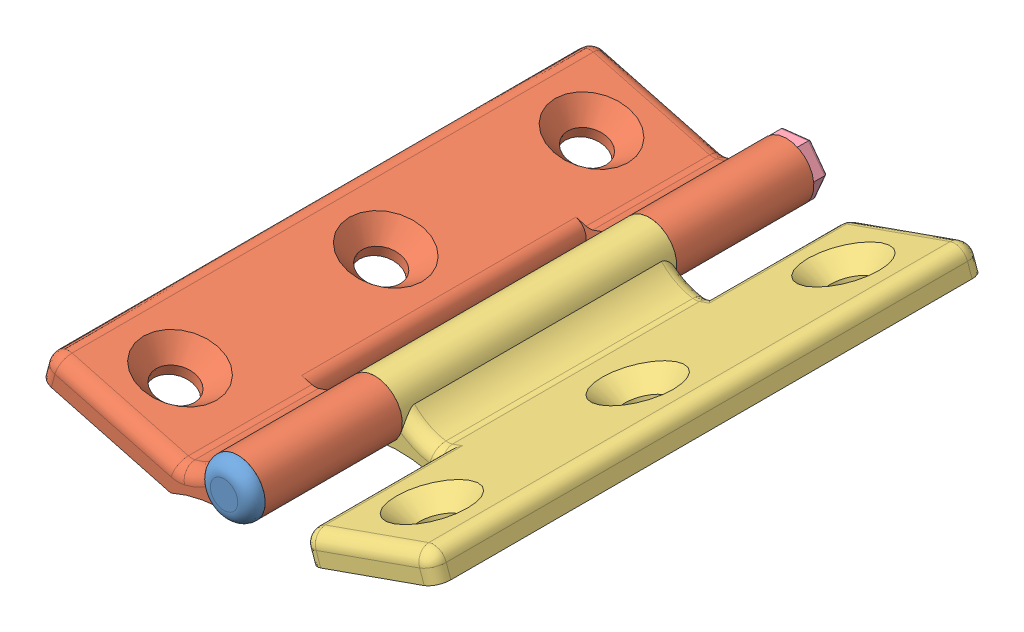
SolidWorks assembly Hinge assembly, configuration Default. Lengths in mm.
Overall size (29.09 10.98 42.19).
4 component instances, 4 part files, 7 mates.
Components (placement in the parent):
- Pin-1: Pin [Default] at (19.366 29.4002 47.4198) x (0.054068 0.998537 0) z (0 0 1) size (4.01 4.01 42.01)
- Hinge 1-1: Hinge 1 [Default] at (6.4153 19.985 47.4198) x (-0.966527 0.256565 0) z (-0.256565 -0.966527 0) size (16 40.18 6)
- Hinge 2-1: Hinge 2 [Default] at (25.3691 20.74 7.4198) x (0.94306 0.332623 0) z (0.332623 -0.94306 0) size (16 40 6)
- Pin Nut-1: Pin Nut [Default] at (15.8837 20.5755 6.4198) x (0.172658 -0.984982 0) z (-0.984982 -0.172658 0) size (3.6 1.18 3.99)
Mates (geometry in assembly coordinates):
- Concentric1: concentric: circle of assembly; circle of assembly; circle of Pin-1; circle of Hinge 1-1
- Distance3: distance = 0 mm: plane of assembly; plane of assembly; plane of Hinge 1-1 through (15.0673 8.6041 47.4198) normal (0 0 1); plane of Pin-1 through (19.366 29.4002 47.4198) normal (0 0 -1)
- Concentric2: concentric: circle of assembly; circle of assembly; circle of Pin-1; circle of Pin Nut-1
- Coincident4: coincident: plane of assembly; plane of assembly; plane of Hinge 1-1 through (15.0673 8.6041 7.4198) normal (0 0 -1); plane of Pin Nut-1 through (15.8837 20.5755 7.4198) normal (0 0 1)
- Concentric3: concentric: circle of assembly; circle of assembly; circle of Hinge 1-1; circle of Hinge 2-1
- Distance2: distance = 0 mm: plane of assembly; plane of assembly; plane of Hinge 1-1 through (-3.8473 -18.676 17.4198) normal (0 0 1); plane of Hinge 2-1 through (38.674 -16.9824 17.4198) normal (0 0 -1)
- LimitAngle1: limit planar angle = 2.543043 rad: line of assembly; line of assembly; line of Hinge 1-1 through (2.8058 21.9778 46.4198) axis (0.966527 -0.256565 0); line of Hinge 2-1 through (21.2643 20.3525 46.4198) axis (0.94306 0.332623 0)
